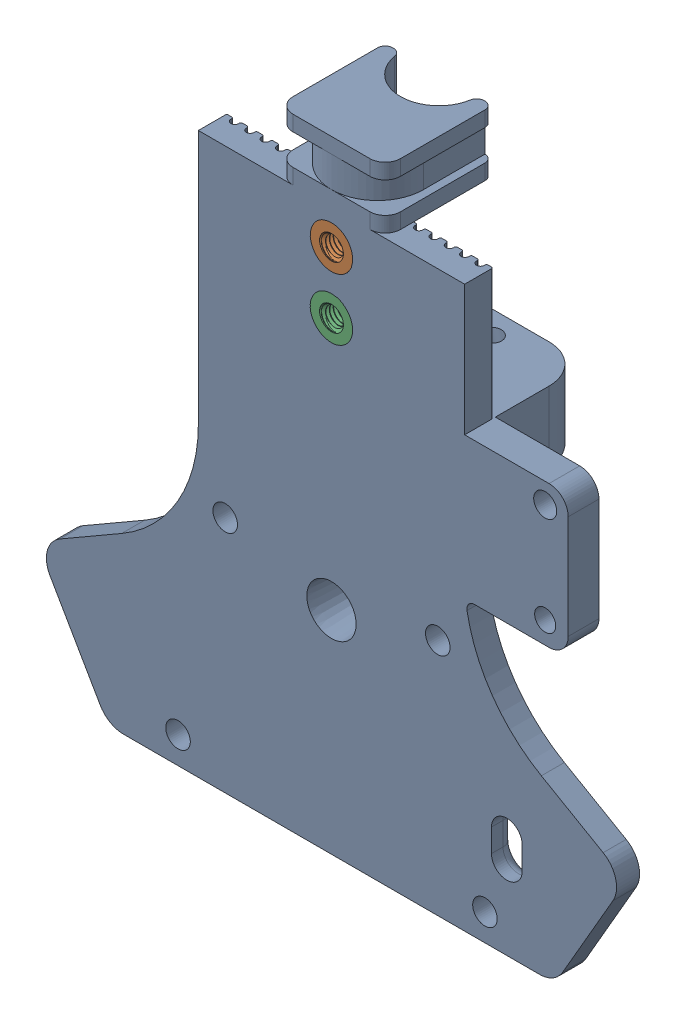
SolidWorks assembly carriage_back_plate_with_inserts, configuration Default. Lengths in mm.
Overall size (74.3 81.02 16.04).
3 component instances, 2 part files, 0 mates.
Components (placement in the parent):
- coupling_plate_Carriage Back Plate-1: coupling_plate_Carriage Back Plate [Default] at (97.5575 375.4795 75.9434) size (74.3 81.02 16)
- m3_heat_set_insert_94180A331_94180A331-1: m3_heat_set_insert_94180A331_94180A331 [Default] at (97.5575 416.4295 42.1434) x (0.303083 -0.952964 0) z (-0.952964 -0.303083 0) size (5.56 3.88 5.56)
- m3_heat_set_insert_94180A331_94180A331-2: m3_heat_set_insert_94180A331_94180A331 [Default] at (97.5575 408.4295 42.1434) x (0.303083 -0.952964 0) z (-0.952964 -0.303083 0) size (5.56 3.88 5.56)
